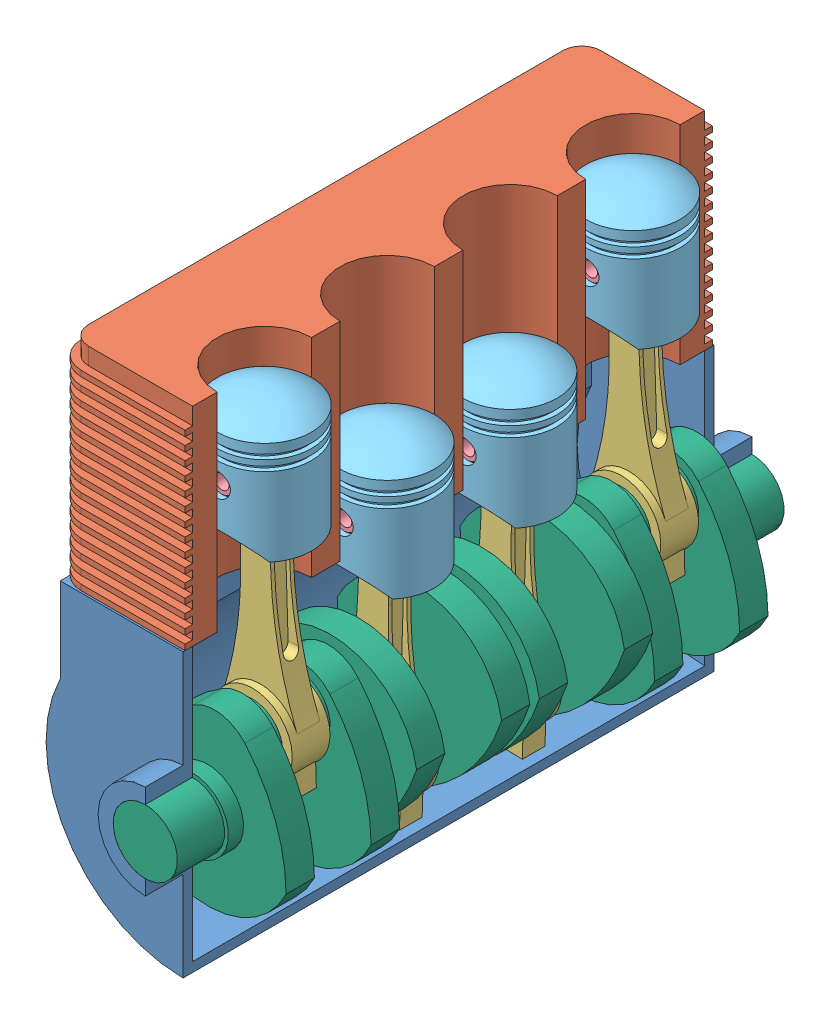
SolidWorks assembly 4 piston cylinder, configuration Default. Lengths in mm.
Overall size (122.91 259.5 321).
15 component instances, 6 part files, 31 mates.
Components (placement in the parent):
- engine lower case-1: engine lower case [Default] at (136.9409 146.0124 410.0697) size (72.5 149.5 321)
- engine upper case-1: engine upper case [Default] at (136.9409 223.0124 405.0697) x (0 0 -1) z (1 0 0) size (279 110 69)
- Connecting rod-1: Connecting rod [Default] at (140.6967 170.7286 367.0697) x (0.99951 0.031298 0) z (0 0 1) size (42 160.15 20)
- PISTON PIN-1: PISTON PIN [Default] at (136.9409 290.6699 367.0697) size (12.5 12.5 45)
- PISTON-1: PISTON [Default] at (136.9409 260.1699 367.0697) size (50 64.17 50)
- crank shaft-1: crank shaft [Default] at (136.9409 146.0124 405.0697) x (0 0 -1) z (0.988651 -0.150229 0) size (321 92 88)
- PISTON-4: PISTON [Default] at (136.9409 260.1699 172.0697) x (-1 0 0) z (0 0 -1) size (50 64.17 50)
- PISTON PIN-2: PISTON PIN [Default] at (136.9409 290.6699 172.0697) x (-0.173648 0.984808 0) z (0 0 -1) size (12.5 12.5 45)
- Connecting rod-4: Connecting rod [Default] at (140.6967 170.7286 172.0697) x (-0.99951 -0.031298 0) z (0 0 -1) size (42 160.15 20)
- PISTON-6: PISTON [Default] at (136.9409 210.7373 302.0697) size (50 64.17 50)
- Connecting rod-6: Connecting rod [Default] at (133.1852 121.2961 302.0697) x (0.99951 -0.031298 0) z (0 0 1) size (42 160.15 20)
- PISTON PIN-4: PISTON PIN [Default] at (136.9409 241.2373 302.0697) size (12.5 12.5 45)
- PISTON-7: PISTON [Default] at (136.9409 210.7373 237.0697) x (-1 0 0) z (0 0 -1) size (50 64.17 50)
- PISTON PIN-5: PISTON PIN [Default] at (136.9409 241.2373 237.0697) x (-0.173648 0.984808 0) z (0 0 -1) size (12.5 12.5 45)
- Connecting rod-7: Connecting rod [Default] at (133.1852 121.2961 237.0697) x (-0.99951 0.031298 0) z (0 0 -1) size (42 160.15 20)
Mates (geometry in assembly coordinates):
- Coincident8: coincident anti-aligned: plane of engine lower case-1 through (136.9409 223.0124 405.0697) normal (0 1 0); plane of engine upper case-1 through (81.9409 223.0124 395.0697) normal (0 -1 0)
- Coincident9: coincident aligned: plane of engine lower case-1 through (136.9409 171.0124 405.0697) normal (1 0 0); plane of engine upper case-1 through (136.9409 333.0124 405.0697) normal (1 0 0)
- Width2: width anti-aligned: plane of engine lower case-1 through (136.9409 146.0124 410.0697) normal (0 0 1); plane of engine lower case-1 through (136.9409 146.0124 129.0697) normal (0 0 -1); plane of engine upper case-1 through (136.9409 333.0124 134.0697) normal (0 0 -1); plane of engine upper case-1 through (136.9409 333.0124 405.0697) normal (0 0 1)
- Concentric2: concentric anti-aligned: cylinder of engine lower case-1 through (136.9409 146.0124 405.0697) axis (0 0 1) radius 17; cylinder of crank shaft-1 through (136.9409 146.0124 430.0697) axis (0 0 -1) radius 17
- Coincident10: coincident aligned: plane of engine lower case-1 through (136.9409 146.0124 430.0697) normal (0 0 1); plane of crank shaft-1 through (136.9409 146.0124 430.0697) normal (0 0 1)
- Concentric3: concentric anti-aligned: cylinder of PISTON PIN-1 through (136.9409 244.9997 389.5697) axis (0 0 -1) radius 6.25; cylinder of PISTON-1 through (136.9409 244.9997 342.0697) axis (0 0 1) radius 6.25
- Width6: width anti-aligned: plane of PISTON-1 through (136.9409 244.9997 379.0697) normal (0 0 -1); plane of PISTON-1 through (136.9409 244.9997 355.0697) normal (0 0 1); plane of PISTON PIN-1 through (136.9409 244.9997 389.5697) normal (0 0 1); plane of PISTON PIN-1 through (136.9409 244.9997 344.5697) normal (0 0 -1)
- Concentric4: concentric aligned: cylinder of Connecting rod-1 through (136.9409 244.9997 377.0697) axis (0 0 -1) radius 6.25; cylinder of PISTON PIN-1 through (136.9409 244.9997 389.5697) axis (0 0 -1) radius 6.25
- Width7: width aligned: plane of PISTON-1 through (136.9409 244.9997 355.0697) normal (0 0 1); plane of PISTON-1 through (136.9409 244.9997 379.0697) normal (0 0 -1); plane of Connecting rod-1 through (136.9409 244.9997 377.0697) normal (0 0 1); plane of Connecting rod-1 through (136.9409 244.9997 357.0697) normal (0 0 -1)
- Concentric5: concentric anti-aligned: cylinder of Connecting rod-1 through (122.0563 125.9264 377.0697) axis (0 0 -1) radius 16; cylinder of crank shaft-1 through (122.0563 125.9264 367.0697) axis (0 0 1) radius 16
- Width8: width anti-aligned: plane of crank shaft-1 through (119.6098 160.3395 382.0697) normal (0 0 -1); plane of crank shaft-1 through (119.6098 160.3395 352.0697) normal (0 0 1); plane of Connecting rod-1 through (122.0563 125.9264 377.0697) normal (0 0 1); plane of Connecting rod-1 through (122.0563 125.9264 357.0697) normal (0 0 -1)
- Concentric6: concentric anti-aligned: cylinder of engine upper case-1 through (136.9409 333.0124 367.0697) axis (0 -1 0) radius 25; cylinder of PISTON-1 through (136.9409 276.9997 367.0697) axis (0 1 0) radius 25
- Concentric11: concentric anti-aligned: cylinder of PISTON-4 through (136.9409 244.9997 197.0697) axis (0 0 -1) radius 6.25; cylinder of PISTON PIN-2 through (136.9409 244.9997 149.5697) axis (0 0 1) radius 6.25
- Width13: width anti-aligned: plane of PISTON-4 through (136.9409 244.9997 160.0697) normal (0 0 1); plane of PISTON-4 through (136.9409 244.9997 184.0697) normal (0 0 -1); plane of PISTON PIN-2 through (136.9409 244.9997 149.5697) normal (0 0 -1); plane of PISTON PIN-2 through (136.9409 244.9997 194.5697) normal (0 0 1)
- Concentric12: concentric aligned: cylinder of PISTON PIN-2 through (136.9409 244.9997 149.5697) axis (0 0 1) radius 6.25; cylinder of Connecting rod-4 through (136.9409 244.9997 162.0697) axis (0 0 1) radius 6.25
- Width14: width aligned: plane of PISTON-4 through (136.9409 244.9997 184.0697) normal (0 0 -1); plane of PISTON-4 through (136.9409 244.9997 160.0697) normal (0 0 1); plane of Connecting rod-4 through (136.9409 244.9997 162.0697) normal (0 0 -1); plane of Connecting rod-4 through (136.9409 244.9997 182.0697) normal (0 0 1)
- Concentric13: concentric anti-aligned: cylinder of crank shaft-1 through (122.0563 125.9264 172.0697) axis (0 0 -1) radius 16; cylinder of Connecting rod-4 through (122.0563 125.9264 162.0697) axis (0 0 1) radius 16
- Concentric14: concentric anti-aligned: cylinder of engine upper case-1 through (136.9409 333.0124 172.0697) axis (0 -1 0) radius 25; cylinder of PISTON-4 through (136.9409 276.9997 172.0697) axis (0 1 0) radius 25
- Concentric17: concentric anti-aligned: cylinder of PISTON-6 through (136.9409 285.1716 277.0697) axis (0 0 1) radius 6.25; cylinder of PISTON PIN-4 through (136.9409 285.1716 324.5697) axis (0 0 -1) radius 6.25
- Width17: width aligned: plane of PISTON-6 through (136.9409 285.1716 290.0697) normal (0 0 1); plane of PISTON-6 through (136.9409 285.1716 314.0697) normal (0 0 -1); plane of PISTON PIN-4 through (136.9409 285.1716 324.5697) normal (0 0 1); plane of PISTON PIN-4 through (136.9409 285.1716 279.5697) normal (0 0 -1)
- Concentric18: concentric aligned: cylinder of Connecting rod-6 through (136.9409 285.1716 312.0697) axis (0 0 -1) radius 6.25; cylinder of PISTON PIN-4 through (136.9409 285.1716 324.5697) axis (0 0 -1) radius 6.25
- Width18: width anti-aligned: plane of PISTON-6 through (136.9409 285.1716 314.0697) normal (0 0 -1); plane of PISTON-6 through (136.9409 285.1716 290.0697) normal (0 0 1); plane of Connecting rod-6 through (136.9409 285.1716 312.0697) normal (0 0 1); plane of Connecting rod-6 through (136.9409 285.1716 292.0697) normal (0 0 -1)
- Concentric19: concentric anti-aligned: cylinder of crank shaft-1 through (151.8256 166.0983 287.0697) axis (0 0 1) radius 16; cylinder of Connecting rod-6 through (151.8256 166.0983 312.0697) axis (0 0 -1) radius 16
- Width19: width aligned: plane of crank shaft-1 through (110.7477 148.3807 287.0697) normal (0 0 1); plane of crank shaft-1 through (110.7477 148.3807 317.0697) normal (0 0 -1); plane of Connecting rod-6 through (151.8256 166.0983 312.0697) normal (0 0 1); plane of Connecting rod-6 through (151.8256 166.0983 292.0697) normal (0 0 -1)
- Concentric20: concentric anti-aligned: cylinder of engine upper case-1 through (136.9409 333.0124 302.0697) axis (0 -1 0) radius 25; cylinder of PISTON-6 through (136.9409 317.1716 302.0697) axis (0 1 0) radius 25
- Concentric21: concentric anti-aligned: cylinder of PISTON-7 through (136.9409 285.1716 262.0697) axis (0 0 -1) radius 6.25; cylinder of PISTON PIN-5 through (136.9409 285.1716 214.5697) axis (0 0 1) radius 6.25
- Width20: width aligned: plane of PISTON-7 through (136.9409 285.1716 249.0697) normal (0 0 -1); plane of PISTON-7 through (136.9409 285.1716 225.0697) normal (0 0 1); plane of PISTON PIN-5 through (136.9409 285.1716 214.5697) normal (0 0 -1); plane of PISTON PIN-5 through (136.9409 285.1716 259.5697) normal (0 0 1)
- Concentric22: concentric aligned: cylinder of PISTON PIN-5 through (136.9409 285.1716 214.5697) axis (0 0 1) radius 6.25; cylinder of Connecting rod-7 through (136.9409 285.1716 227.0697) axis (0 0 1) radius 6.25
- Width21: width anti-aligned: plane of PISTON-7 through (136.9409 285.1716 225.0697) normal (0 0 1); plane of PISTON-7 through (136.9409 285.1716 249.0697) normal (0 0 -1); plane of Connecting rod-7 through (136.9409 285.1716 227.0697) normal (0 0 -1); plane of Connecting rod-7 through (136.9409 285.1716 247.0697) normal (0 0 1)
- Concentric23: concentric anti-aligned: cylinder of crank shaft-1 through (151.8256 166.0983 252.0697) axis (0 0 -1) radius 16; cylinder of Connecting rod-7 through (151.8256 166.0983 227.0697) axis (0 0 1) radius 16
- Concentric24: concentric anti-aligned: cylinder of engine upper case-1 through (136.9409 333.0124 237.0697) axis (0 -1 0) radius 25; cylinder of PISTON-7 through (136.9409 317.1716 237.0697) axis (0 1 0) radius 25
